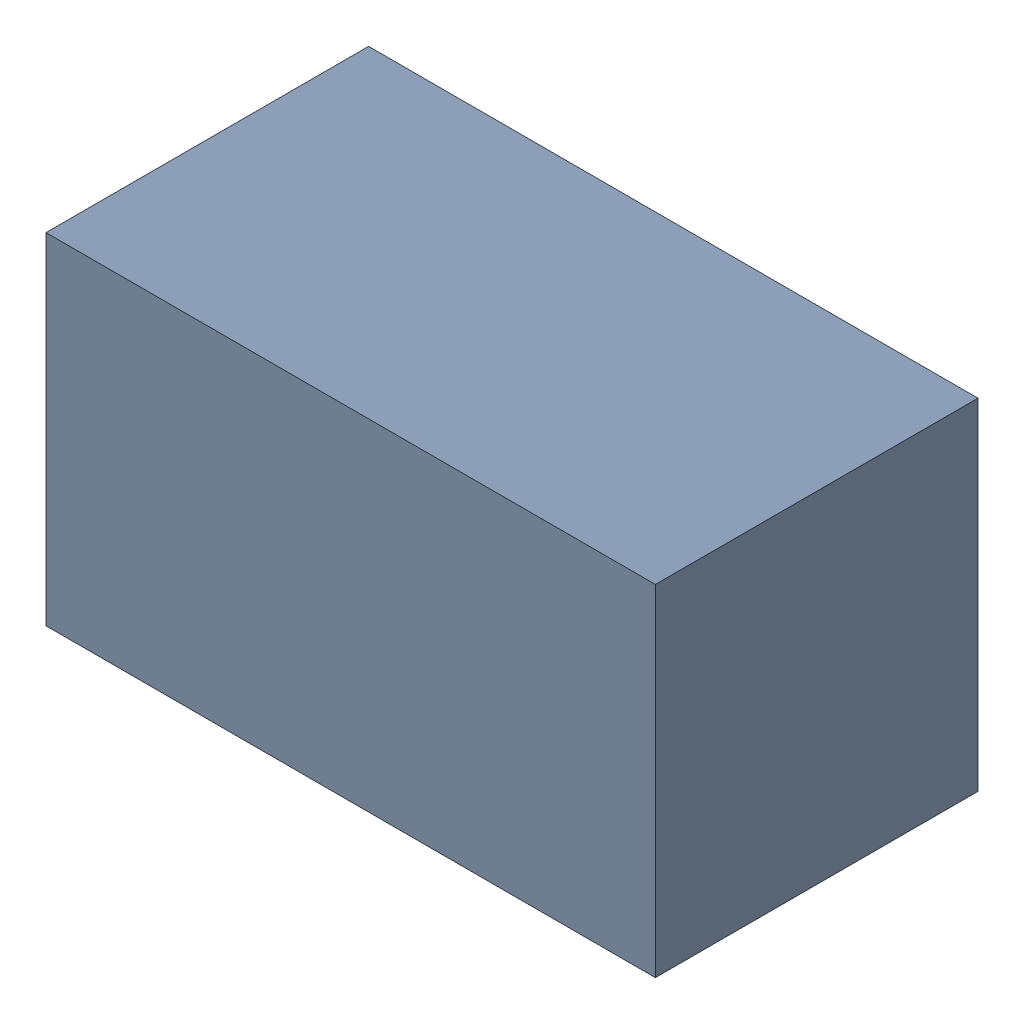
SolidWorks assembly R202, configuration Standard. Lengths in mm.
Overall size (1.7 0.95 0.9).
2 component instances, 1 part files, 0 mates.
Components (placement in the parent):
- 885541288-1: 885541288 [Standard] at (3.65 -20.4 0) size (1.7 0.95 0.9)
  - Extruded_10-1: Extruded_10 [Standard] at origin size (1.7 0.95 0.9)
